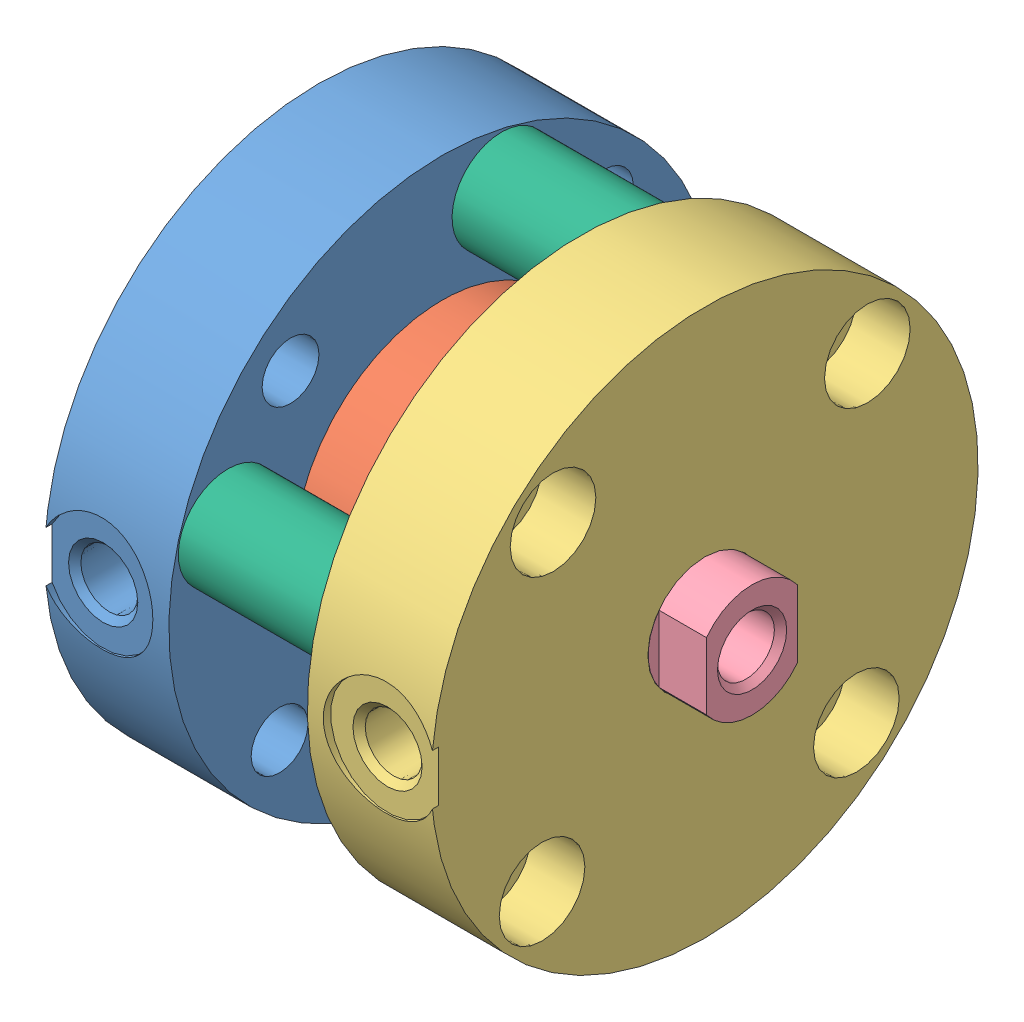
SolidWorks assembly FO-040_5_2_14, configuration Default. Lengths in mm.
Overall size (30.46 38.1 38.1).
9 component instances, 6 part files, 0 mates.
Components (placement in the parent):
- _04-2-0.13-FO1_BM_heads-1: _04-2-0.13-FO1_BM_heads [Default] at (8.636 0 0) x (0 0 -1) z (0 1 0) size (38.1 8.87 38.1)
- _040.72-FO1_BM_tube-1: _040.72-FO1_BM_tube [Default] at (4.318 0 0) x (0 0 -1) z (0 -1 0) size (20.62 18.29 20.62)
- _04-1-0.13-FO1_BM_heads-1: _04-1-0.13-FO1_BM_heads [Default] at (18.288 0 0) x (0 0 -1) z (0 -1 0) size (38.1 8.87 38.1)
- _041.021.02-FO1_BM_rod-1: _041.021.02-FO1_BM_rod [Default] at (4.318 0 0) x (0 0 -1) z (0 -1 0) size (7.87 25.91 7.87)
- _0.750.22-rod_part-1: _0.750.22-rod_part [Default] at (4.318 0 0) x (0 0 -1) z (-1 0 0) size (19.05 19.05 5.59)
- _040.72-FO1_BM_r-1: _040.72-FO1_BM_r [Default] at (22.606 4.1406 14.9305) x (0 0 -1) z (0 1 0) size (6.91 18.29 6.91)
- _040.72-FO1_BM_r-2: _040.72-FO1_BM_r [Default] at (22.606 14.9305 -4.1406) x (0 0 -1) z (0 1 0) size (6.91 18.29 6.91)
- _040.72-FO1_BM_r-3: _040.72-FO1_BM_r [Default] at (22.606 -4.1406 -14.9305) x (0 0 -1) z (0 1 0) size (6.91 18.29 6.91)
- _040.72-FO1_BM_r-4: _040.72-FO1_BM_r [Default] at (22.606 -14.9305 4.1406) x (0 0 -1) z (0 1 0) size (6.91 18.29 6.91)
